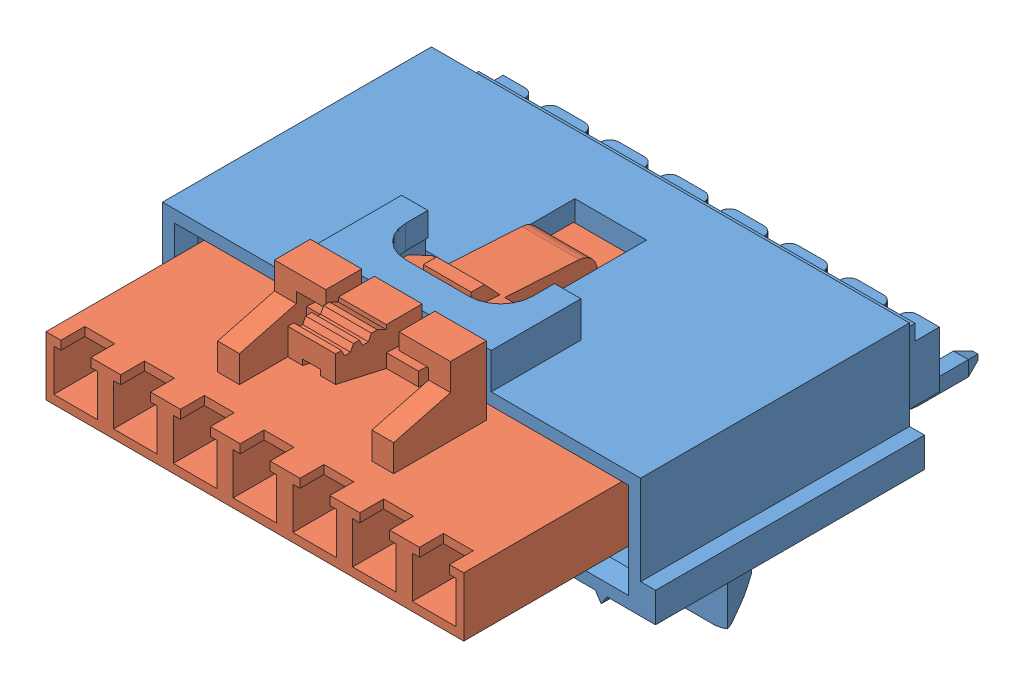
SolidWorks assembly Assem1, configuration Default. Lengths in mm.
Overall size (21.59 9.91 23.17).
2 component instances, 2 part files, 0 mates.
Components (placement in the parent):
- 015913074-1: 015913074 [Default] at (10.5006 14.096 16.443) size (21.59 9.35 16.76)
- 050579407-1: 050579407 [Default] at (10.6703 14.5401 20.9413) x (-1 0 0) z (0 -1 0) size (17.75 15.24 6.45)
